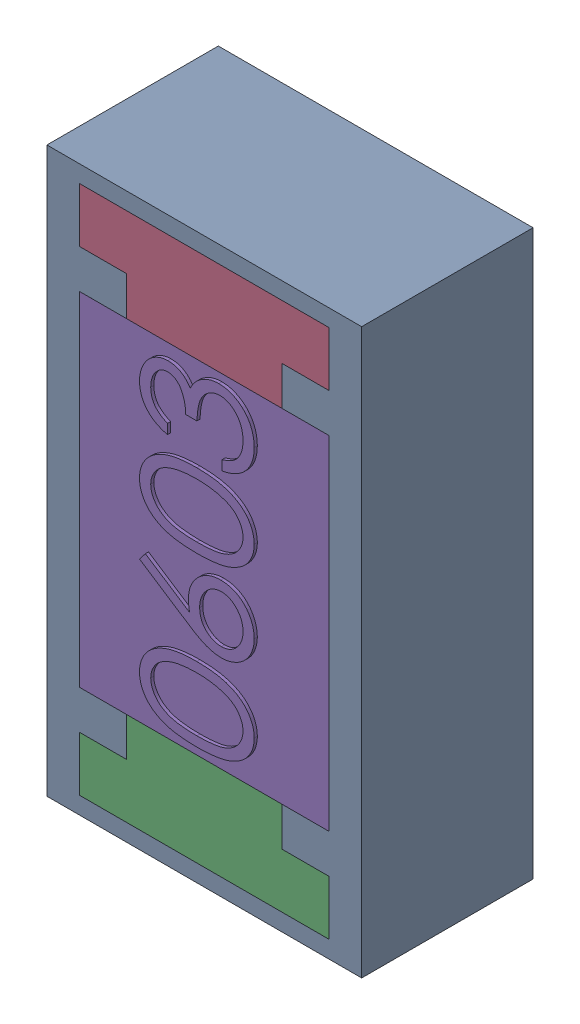
SolidWorks assembly R15, configuration Default. Lengths in mm.
Overall size (1.01 1.81 0.56).
3 component instances, 2 part files, 0 mates.
Components (placement in the parent):
- 1088887696-1: 1088887696 [Default] at (3.525 10.2 0) size (1.01 1.81 0.55)
  - Extruded-29-1: Extruded-29 [Default] at origin size (1.01 1.81 0.55)
- R0603-1: R0603 [Default] at (3.5249 10.2001 0) x (0 1 0) z (1 0 0) size (1.7 0.56 0.8)
